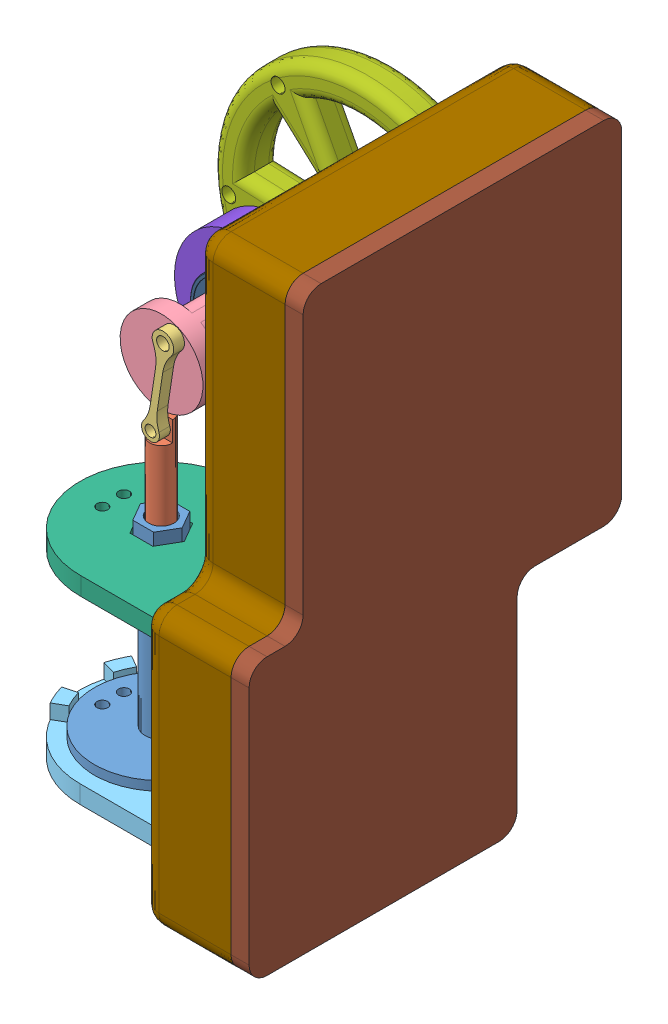
SolidWorks assembly engine, configuration Default. Lengths in mm.
Overall size (108.68 162.99 120.01).
15 component instances, 13 part files, 44 mates.
Components (placement in the parent):
- actuater-1: actuater [Default] at origin size (37.1 77.79 37.1) (flexible)
  - Spool_V1-1: Spool_V1 [Default] at (35.0022 -0.1462 27.5826) size (37.1 53.12 37.1)
  - rod-1: rod [Default] at (35.0022 77.6418 27.5826) x (-1 0 0) z (0 -1 0) size (6.35 6.35 45.12)
- linkage-2: linkage [Default] at (38.4493 97.5834 30.5826) x (-0.149874 -0.988705 0) z (0.988705 -0.149874 0) size (28.5 3 6)
- pin-2: pin [Default] at (35.0022 74.8431 24.9704) x (0.997592 0.06936 0) z (0.06936 -0.997592 0) size (2.5 16 2.5) (hidden)
- spinner-1: spinner [Default] at (35.0682 90 -77.4174) x (0.407215 0.913332 0) z (0 0 1) size (23 23 64.21)
- base-1: base [Default] at (35.0022 -5.1462 27.5826) x (0 1 0) z (0 0 1) size (9 48.18 45.14)
- base2-1: base2 [Default] at (35.0022 49.9738 27.5826) x (0 -1 0) z (0.266317 0 0.963886) size (52.64 53.27 51.14)
- holder-2: holder [Default] at (35.0682 90 -36.6259) x (0 0 1) z (-0.462866 0.886428 0) size (10.59 80.54 80.54)
- holder2-1: holder2 [Default] at (35.0682 90 5.0146) x (0 0 -1) z (1 0 0) size (10 37.96 44.48)
- Part2-1: Part2 [Default] at (63.5682 -5.1462 50.1505) x (0 -1 0) z (1 0 0) size (158.81 103.42 25)
- 608RS-1: 608RS [Default] at (35.0682 90 -5.0854) x (0.988989 0.14799 0) z (0 0 1) size (22 22 7)
- 608RS-2: 608RS [Default] at (35.0682 90 1.7146) x (0.99964 0.026848 0) z (0 0 1) size (22 22 7)
- bottomlid-1: bottomlid [Default] at (114.8906 -3.1844 28.8479) x (0 -1 0) z (1 0 0)
- Part6^engine-1: Part6^engine [Default] at (83.5682 -5.1462 50.1505) x (0 -1 0) z (1 0 0) size (158.81 115.67 10)
Mates (geometry in assembly coordinates):
- Parallel2: parallel anti-aligned: plane of actuater-1/rod-1 through (35.0022 77.6418 27.5826) normal (0 0 1); plane of linkage-2 through (48.2867 89.0848 27.5826) normal (0 0 -1)
- Concentric2: concentric anti-aligned: circle of actuater-1/rod-1; circle of linkage-2
- Coincident5: coincident anti-aligned: plane of actuater-1/rod-1 through (35.0022 77.6418 27.5826) normal (0 0 1); plane of linkage-2 through (48.2867 89.0848 27.5826) normal (0 0 -1)
- Coincident10: coincident aligned: plane of actuater-1/rod-1 through (35.0022 77.6418 27.5826) normal (0 0 1); plane of spinner-1 through (35.0682 90 27.5826) normal (0 0 1)
- Perpendicular1: perpendicular: cylinder of actuater-1/Spool_V1-1 through (35.0022 22.4138 27.5826) axis (0 -1 0) radius 4.55; cylinder of spinner-1 through (35.0682 90 22.5826) axis (0 0 -1) radius 5
- Coincident20: coincident: point of spinner-1; plane of assembly
- Concentric6: concentric anti-aligned: cylinder of actuater-1/rod-1 through (35.0022 74.8431 20.5826) axis (0 0 1) radius 1.5; cylinder of pin-2 through (35.0022 74.8431 30.9704) axis (0 0 -1) radius 1.25
- Concentric10: concentric aligned: cylinder of linkage-2 through (38.4493 97.5834 27.5826) axis (0 0 1) radius 1.75; cylinder of spinner-1 through (38.4493 97.5834 -11.6259) axis (0 0 1) radius 1.5
- Coincident23: coincident anti-aligned: plane of actuater-1/Spool_V1-1 through (35.0022 -0.1462 27.5826) normal (0 -1 0); plane of base-1 through (35.0022 -0.1462 27.5826) normal (0 1 0)
- Coincident25: coincident: plane of actuater-1/Spool_V1-1 through (35.0022 44.9738 27.5826) normal (0 1 0); plane of base2-1 through (35.0022 44.9738 27.5826) normal (0 -1 0)
- Concentric13: concentric aligned: circle of actuater-1/Spool_V1-1; circle of base-1
- Parallel5: parallel anti-aligned: line of base2-1 through (58.5682 44.9738 45.1005) axis (0 -1 0); line of basebot-1 through (58.5682 -0.0962 50.1505) axis (0 1 0)
- Parallel6: parallel aligned: line of base2-1 through (58.5682 44.9738 10.0646) axis (0 -1 0); line of basebot-1 through (58.5682 44.9238 5.0146) axis (0 -1 0)
- Parallel7: parallel anti-aligned: plane of base2-1 through (58.5682 81.778 10.0646) normal (1 0 0); plane of basebot-1 through (58.5682 -5.1462 50.1505) normal (-1 0 0)
- Coincident32: coincident anti-aligned: plane of base2-1 through (58.5682 81.778 10.0646) normal (1 0 0); plane of basebot-1 through (58.5682 -5.1462 50.1505) normal (-1 0 0)
- Coincident35: coincident aligned: plane of base-1 through (60.6182 -5.1462 5.0146) normal (0 0 -1); plane of basebot-1 through (58.5682 -5.1462 5.0146) normal (0 0 -1)
- Parallel12: parallel aligned: cylinder of spinner-1 through (35.0682 90 22.5826) axis (0 0 -1) radius 5; line of basebot-1 through (58.5682 108.9805 50.1505) axis (0 0 -1)
- Parallel15: parallel anti-aligned: plane of spinner-1 through (35.0682 90 14.5826) normal (0 0 -1); plane of holder-2 through (35.0682 90 -26.6259) normal (0 0 1)
- Concentric14: concentric aligned: cylinder of spinner-1 through (35.0682 90 13.3741) axis (0 0 -1) radius 4.025; cylinder of holder-2 through (35.0682 90 -26.6259) axis (0 0 -1) radius 4.025
- Coincident43: coincident anti-aligned: plane of spinner-1 through (37.2843 91.1572 -26.6259) normal (0.886428 0.462866 0); plane of holder-2 through (37.2843 91.1572 -26.6259) normal (-0.886428 -0.462866 0)
- Coincident46: coincident anti-aligned: plane of spinner-1 through (35.0682 90 -26.6259) normal (0 0 -1); plane of holder-2 through (35.0682 90 -26.6259) normal (0 0 1)
- Parallel17: parallel anti-aligned: plane of spinner-1 through (35.0682 90 14.5826) normal (0 0 -1); plane of holder2-1 through (35.0682 90 5.0146) normal (0 0 1)
- Concentric15: concentric anti-aligned: cylinder of spinner-1 through (35.0682 90 13.3741) axis (0 0 -1) radius 4.025; cylinder of holder2-1 through (35.0682 90 -4.9854) axis (0 0 1) radius 18.9805
- Coincident49: coincident: point of spinner-1; plane of assembly
- Parallel18: parallel aligned: plane of base2-1 through (35.0022 49.9738 27.5826) normal (0 1 0); plane of holder2-1 through (58.5682 108.9805 -4.9854) normal (0 1 0)
- Coincident51: coincident anti-aligned: line of basebot-1 through (58.5682 71.0195 5.0146) axis (1 0 0); line of holder2-1 through (60.5682 71.0195 5.0146) axis (-1 0 0)
- InPlace1: in place: plane of ? through (63.3682 -5.1462 50.1505) normal (1 0 0); plane of ? through (63.3682 0 0) normal (1 0 0); moOrthogonalPlaneRef_w of ? through (63.3682 -5.1462 50.1505) normal (1 0 0); plane of ? through (63.3682 0 0) normal (0 1 0); plane of ? through (63.3682 -5.1462 50.1505) normal (1 0 0); plane of ? through (63.3682 0 0) normal (0 0 -1); plane of ? through (63.5682 -5.1462 50.1505) normal (1 0 0); unknown of Part2-1
- Coincident52: coincident aligned: plane of ?; plane of Part2-1
- Coincident53: coincident aligned: moOrthogonalPlaneRef_w of basebot-1 through (63.5682 -5.1462 50.1505) normal (0 0 -1); plane of Part2-1 through (63.5682 -5.1462 50.1505) normal (0 0 -1)
- Coincident54: coincident anti-aligned: moOrthogonalPlaneRef_w of basebot-1 through (63.5682 -5.1462 50.1505) normal (0 1 0); plane of Part2-1 through (63.5682 -5.1462 50.1505) normal (0 -1 0)
- Coincident52: coincident anti-aligned: circle of holder2-1; cylinder of 608RS-1 through (35.0682 90 1.9146) axis (0 0 -1) radius 11
- Coincident53: coincident aligned: plane of holder2-1 through (35.0682 90 -4.9854) normal (0 0 -1); plane of 608RS-1 through (35.0682 90 -4.9854) normal (0 0 -1)
- Concentric16: concentric anti-aligned: cylinder of holder2-1 through (35.0682 90 -4.9854) axis (0 0 1) radius 11; cylinder of 608RS-2 through (35.0682 90 8.7146) axis (0 0 -1) radius 11
- Coincident54: coincident anti-aligned: plane of 608RS-1 through (35.0682 90 1.8146) normal (0 0 1); plane of 608RS-2 through (35.0682 90 1.8146) normal (0 0 -1)
- InPlace3: in place: plane of ? through (58.3682 -5.1462 50.1505) normal (-1 0 0); plane of ? through (58.3682 0 0) normal (-1 0 0); plane of ? through (58.3682 -5.1462 50.1505) normal (-1 0 0); plane of ? through (58.3682 0 0) normal (0 1 0); plane of ? through (58.3682 -5.1462 50.1505) normal (-1 0 0); plane of ? through (58.3682 0 0) normal (0 0 1); plane of Part2-1 through (58.5682 -5.1462 50.1505) normal (-1 0 0); unknown of ?
- Coincident58: coincident aligned: plane of Part2-1; plane of ?
- Coincident59: coincident aligned: moOrthogonalPlaneRef_w of Part2-1 through (58.5682 -5.1462 50.1505) normal (0 0 -1); plane of Part5^engine-1 through (58.3682 -5.1462 50.1505) normal (0 0 -1)
- Coincident60: coincident anti-aligned: moOrthogonalPlaneRef_w of Part2-1 through (58.5682 -5.1462 50.1505) normal (0 -1 0); plane of Part5^engine-1 through (58.3682 -5.1462 50.1505) normal (0 1 0)
- Concentric17: concentric: circle of actuater-1/Spool_V1-1; circle of base2-1
- LimitDistance1: limit distance = 27.6679 mm aligned: plane of actuater-1/rod-1 through (35.0022 77.6418 27.5826) normal (0 1 0); plane of base2-1 through (35.0022 49.9738 27.5826) normal (0 1 0)
- InPlace4: in place: plane of Part2-1 through (83.5682 -5.1462 50.1505) normal (1 0 0); plane of ? through (83.5682 0 0) normal (1 0 0); plane of Part2-1 through (83.5682 -5.1462 50.1505) normal (1 0 0); plane of ? through (83.5682 0 0) normal (0 1 0); plane of Part2-1 through (83.5682 -5.1462 50.1505) normal (1 0 0); plane of ? through (83.5682 0 0) normal (0 0 -1); plane of Part2-1 through (83.5682 -5.1462 50.1505) normal (1 0 0); unknown of Part6^engine-1
- Coincident57: coincident aligned: plane of Part2-1; plane of Part6^engine-1
- Coincident58: coincident aligned: moOrthogonalPlaneRef_w of Part2-1 through (83.5682 -5.1462 50.1505) normal (0 0 -1); plane of Part6^engine-1 through (83.5682 -5.1462 50.1505) normal (0 0 -1)
- Coincident59: coincident anti-aligned: moOrthogonalPlaneRef_w of Part2-1 through (83.5682 -5.1462 50.1505) normal (0 1 0); plane of Part6^engine-1 through (83.5682 -5.1462 50.1505) normal (0 -1 0)
